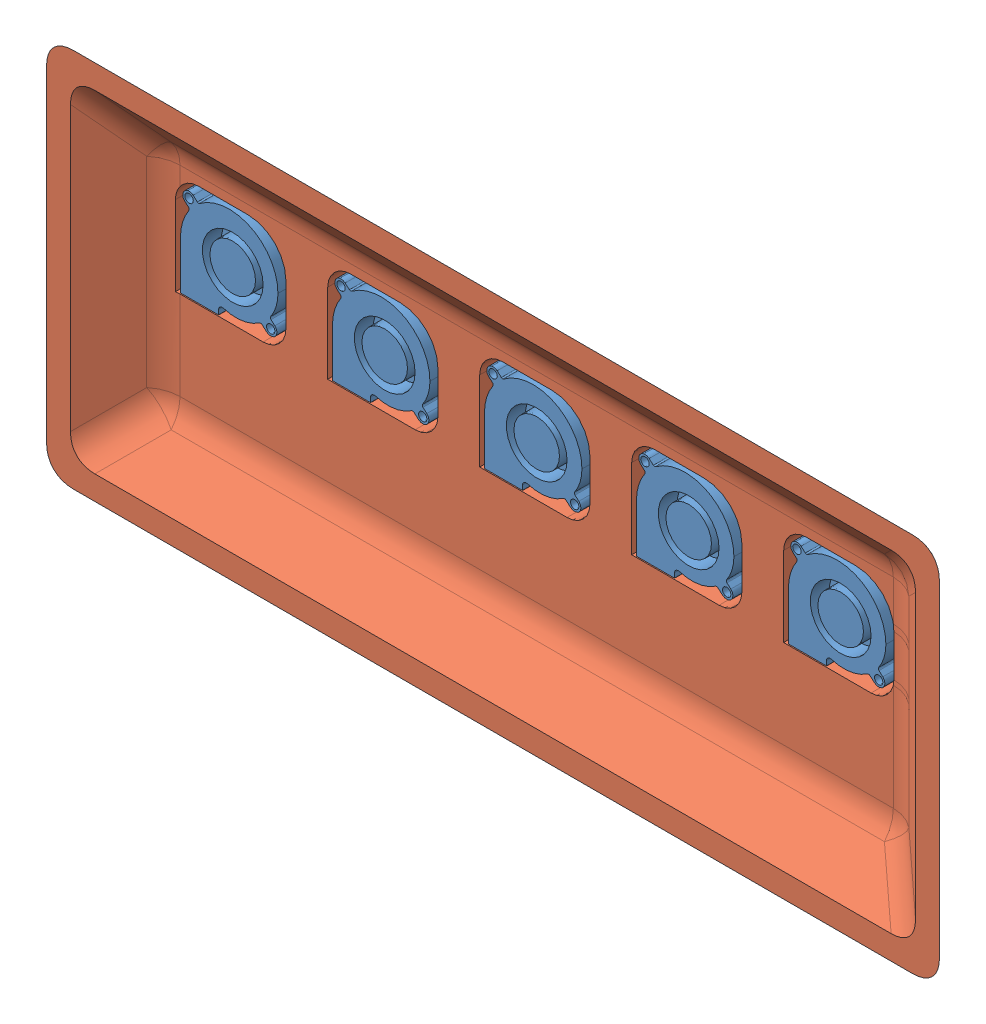
SolidWorks assembly PUTM-H-BT-BB-Fan-Assembly, configuration Domyślna. Lengths in mm.
Overall size (462.03 192.03 40).
6 component instances, 2 part files, 0 mates.
Components (placement in the parent):
- PUTM-H-BT-BB-Fan-6: PUTM-H-BT-BB-Fan [Domyślna] at origin size (51.3 51.07 15)
- PUTM-H-BT-BB-Fan-7: PUTM-H-BT-BB-Fan [Domyślna] at (80 0 0) size (51.3 51.07 15)
- PUTM-H-BT-BB-Fan-8: PUTM-H-BT-BB-Fan [Domyślna] at (160 0 0) size (51.3 51.07 15)
- PUTM-H-BT-BB-Fan-9: PUTM-H-BT-BB-Fan [Domyślna] at (240 0 0) size (51.3 51.07 15)
- PUTM-H-BT-BB-Fan-10: PUTM-H-BT-BB-Fan [Domyślna] at (320 0 0) size (51.3 51.07 15)
- PUTM-BT-BB-Fan_cover-1: PUTM-BT-BB-Fan_cover [Domyślna] at origin size (462.03 192.03 40)
